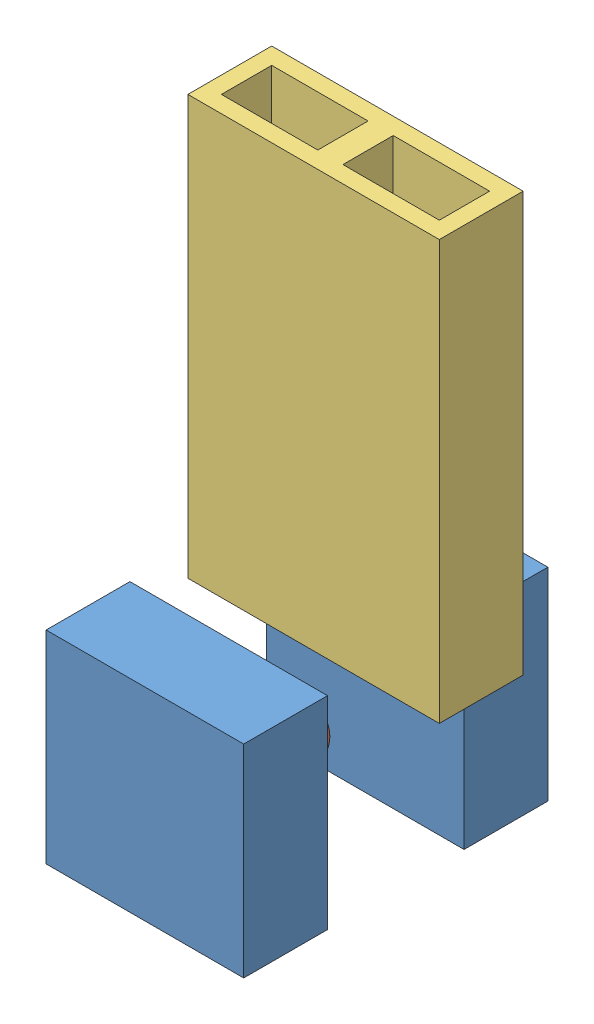
SolidWorks assembly peg and sensor, configuration Default. Lengths in mm.
Overall size (33.83 74.76 36.42).
5 component instances, 3 part files, 6 mates.
Components (placement in the parent):
- sensorbase-1: sensorbase [Default] at (16.928 14.9737 17.6527) size (23.58 24.17 10)
- sensor-1: sensor [Default] at (-7.0645 14.328 27.6527) x (-0.998977 0.045231 0) z (0 0 -1) size (20.42 20.42 3.21)
- sensorbase-3: sensorbase [Default] at (16.7967 14.9737 -8.7717) size (23.58 24.17 10)
- sensor-3: sensor [Default] at (23.354 41.1123 -8.7717) x (0.995634 -0.093342 0) z (0 0 1) size (20.42 20.42 3.21)
- 插头-1: 插头 [默认] at (11.119 77.6915 9.4405) x (1 0 0) z (0 -1 0) size (30 10 50)
Mates (geometry in assembly coordinates):
- 重合1: coincident aligned: plane of sensorbase-1 through (16.928 14.9737 17.6527) normal (0 0 -1); circle of sensor-1
- 重合10: coincident aligned: plane of sensorbase-1 through (15.9908 2.9286 102.3873) normal (0 -1 0); plane of sensorbase-3 through (15.8595 2.9286 75.9628) normal (0 -1 0)
- 相切1: tangent anti-aligned: sphere of sensor-1; plane of 插头-1 through (11.119 27.6915 14.4405) normal (0 0 1)
- 平行1: parallel anti-aligned: plane of sensorbase-1 through (16.928 14.9737 17.6527) normal (0 0 -1); plane of 插头-1 through (11.119 27.6915 14.4405) normal (0 0 1)
- 相切2: tangent anti-aligned: sphere of sensor-3; plane of 插头-1 through (11.119 27.6915 4.4405) normal (0 0 -1)
- 重合12: coincident anti-aligned: plane of sensorbase-3 through (16.7967 14.9737 1.2283) normal (0 0 1); plane of sensor-3 through (2.4912 81.1895 1.2283) normal (0 0 -1)
